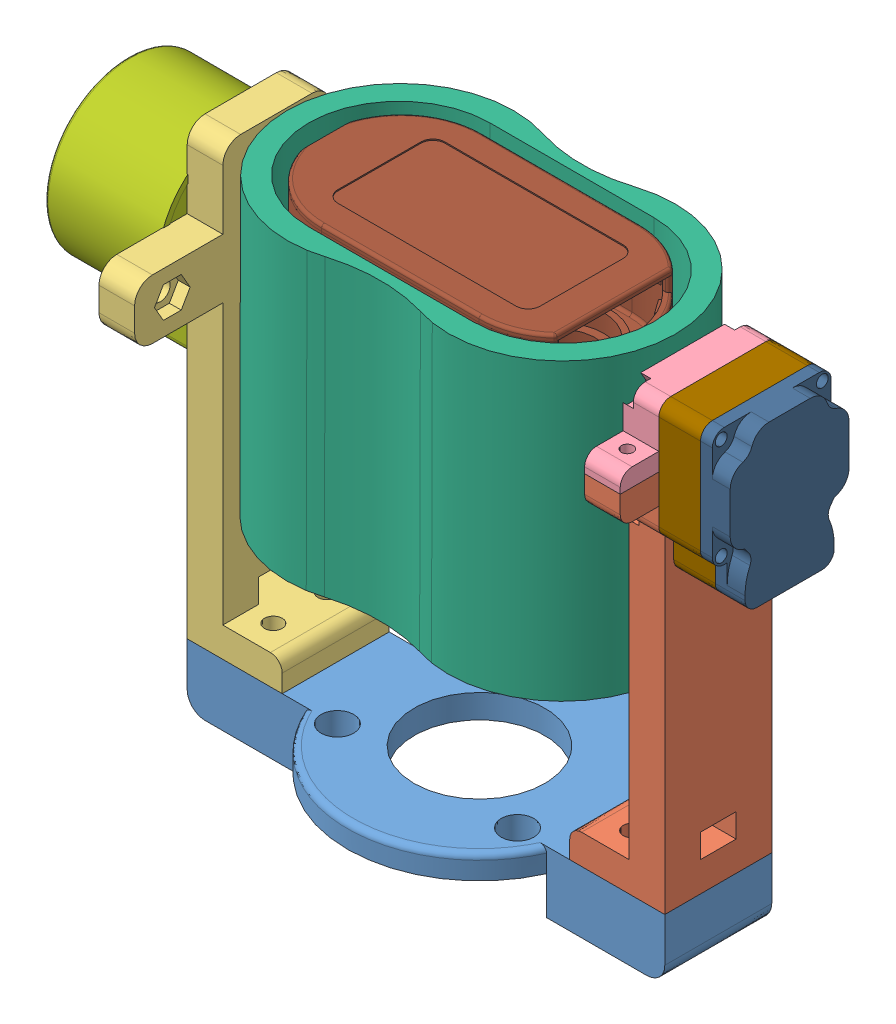
SolidWorks assembly rotating_disk, configuration Default. Lengths in mm.
Overall size (111.27 86.88 47.85).
11 component instances, 11 part files, 27 mates.
Components (placement in the parent):
- rotating_disk_base-1: rotating_disk_base [Default] at (36.4219 21.8509 71.9564) size (80.37 10.47 44.4)
- rotating_disk_encoder_arm-1: rotating_disk_encoder_arm [Default] at (36.4219 21.8509 71.9564) size (16 65 33)
- rotating_disk_stepper_arm-1: rotating_disk_stepper_arm [Default] at (36.4219 21.8509 71.9564) size (16 75 47.85)
- rotating_disk_bearing_holder-1: rotating_disk_bearing_holder [Default] at (66.6873 100.8509 78.7505) size (6 10 33)
- ball_bearing_lidar-1: ball_bearing_lidar [Default] at (74.4089 100.8509 71.9564) x (0 1 0) z (0 0 1) size (12 3.5 12)
- SF10 _attachemnt-1: SF10 _attachemnt [Default] at (36.715 71.7562 116.9127) x (-1 0 0) z (0 -0.999997 0.002567) size (83.46 38.1 49.67)
- Step - 28BYJ-48-1: Step - 28BYJ-48 [Varsayılan] at (-22.665 92.8509 71.9564) x (0 0 -1) z (0 -1 0) size (42 28.9 33.48)
- stepper_encoder-1: stepper_encoder [Default] at (79.195 100.8509 71.9564) x (0 0.002567 0.999997) z (0 -0.999997 0.002567) size (17.8 5 17.8)
- stepper_encoder_case-1: stepper_encoder_case [Default] at (76.6089 100.8509 71.9564) x (0 0 1) z (0 1 0) size (20 7 26)
- stepper_encoder_case_cap-1: stepper_encoder_case_cap [Default] at (83.6089 100.8509 71.9564) x (0 -1 0) z (0 0 1) size (26 5 20)
- sf30c-2: sf30c [Default] at (36.715 98.0933 72.1094) x (1 0 0) z (0 0.999997 -0.002567) size (57.98 31.85 50.31)
Mates (geometry in assembly coordinates):
- Concentric1: concentric aligned: cylinder of rotating_disk_base-1 through (66.6089 -64.1491 67.4564) axis (0 1 0) radius 1.5; cylinder of rotating_disk_encoder_arm-1 through (66.6089 30.8509 67.4564) axis (0 1 0) radius 1.5
- Concentric3: concentric aligned: cylinder of rotating_disk_base-1 through (66.6089 -64.1491 76.4564) axis (0 1 0) radius 1.5; cylinder of rotating_disk_encoder_arm-1 through (66.6089 30.8509 76.4564) axis (0 1 0) radius 1.5
- Coincident2: coincident anti-aligned: plane of rotating_disk_base-1 through (36.4219 35.8509 71.9564) normal (0 1 0); plane of rotating_disk_encoder_arm-1 through (97.3886 35.8509 135.9564) normal (0 -1 0)
- Concentric4: concentric aligned: cylinder of rotating_disk_base-1 through (6.235 -64.1491 76.4564) axis (0 1 0) radius 1.5; cylinder of rotating_disk_stepper_arm-1 through (6.235 -59.1491 76.4564) axis (0 1 0) radius 1.5
- Concentric5: concentric aligned: cylinder of rotating_disk_base-1 through (6.235 -64.1491 67.4564) axis (0 1 0) radius 1.5; cylinder of rotating_disk_stepper_arm-1 through (6.235 -59.1491 67.4564) axis (0 1 0) radius 1.5
- Coincident3: coincident anti-aligned: plane of rotating_disk_base-1 through (36.4219 35.8509 71.9564) normal (0 1 0); plane of rotating_disk_stepper_arm-1 through (-19.0868 35.8509 32.9564) normal (0 -1 0)
- Concentric6: concentric aligned: cylinder of rotating_disk_encoder_arm-1 through (73.6089 89.8509 84.2564) axis (0 1 0) radius 1; cylinder of rotating_disk_bearing_holder-1 through (73.6089 100.0509 84.2564) axis (0 1 0) radius 1
- Concentric7: concentric aligned: cylinder of rotating_disk_encoder_arm-1 through (73.6089 89.8509 59.6564) axis (0 1 0) radius 1; cylinder of rotating_disk_bearing_holder-1 through (73.6089 100.0509 59.6564) axis (0 1 0) radius 1
- Coincident4: coincident anti-aligned: plane of rotating_disk_encoder_arm-1 through (66.6089 100.8509 27.5829) normal (0 1 0); plane of rotating_disk_bearing_holder-1 through (66.6873 100.8509 78.7505) normal (0 -1 0)
- Coincident5: coincident anti-aligned: plane of rotating_disk_bearing_holder-1 through (74.4089 100.8509 71.9564) normal (-1 0 0); plane of ball_bearing_lidar-1 through (74.4089 100.8509 71.9564) normal (1 0 0)
- Concentric8: concentric anti-aligned: cylinder of rotating_disk_bearing_holder-1 through (113.6089 100.8509 71.9564) axis (-1 0 0) radius 5.05; cylinder of ball_bearing_lidar-1 through (70.9089 100.8509 71.9564) axis (1 0 0) radius 4
- Concentric9: concentric anti-aligned: cylinder of ball_bearing_lidar-1 through (70.9089 100.8509 71.9564) axis (1 0 0) radius 4; cylinder of SF10 _attachemnt-1 through (73.195 100.8509 71.9564) axis (-1 0 0) radius 4
- Concentric12: concentric anti-aligned: circle of rotating_disk_stepper_arm-1; cylinder of Step - 28BYJ-48-1 through (-3.765 92.8509 89.4564) axis (-1 0 0) radius 2
- Concentric13: concentric aligned: circle of rotating_disk_stepper_arm-1; circle of Step - 28BYJ-48-1
- Coincident8: coincident anti-aligned: plane of SF10 _attachemnt-1 through (6.235 100.8509 71.9564) normal (-1 0 0); plane of Step - 28BYJ-48-1 through (6.235 101.3509 71.9564) normal (1 0 0)
- Coincident9: coincident anti-aligned: plane of rotating_disk_stepper_arm-1 through (-3.765 60.4422 71.9564) normal (-1 0 0); plane of Step - 28BYJ-48-1 through (-3.765 92.8509 71.9564) normal (1 0 0)
- Coincident12: coincident anti-aligned: plane of rotating_disk_bearing_holder-1 through (76.6089 103.8509 55.4564) normal (1 0 0); plane of stepper_encoder_case-1 through (76.6089 92.8509 79.9564) normal (-1 0 0)
- Concentric26: concentric anti-aligned: cylinder of SF10 _attachemnt-1 through (80.695 102.6149 71.9518) axis (0 0.999997 -0.002567) radius 1; cylinder of stepper_encoder-1 through (80.695 115.8508 71.9179) axis (0 -0.999997 0.002567) radius 1
- Concentric27: concentric aligned: cylinder of SF10 _attachemnt-1 through (73.195 100.8509 71.9564) axis (-1 0 0) radius 4; cylinder of stepper_encoder-1 through (92.195 100.8509 71.9564) axis (-1 0 0) radius 4.075
- Coincident13: coincident anti-aligned: circle of rotating_disk_bearing_holder-1; cylinder of stepper_encoder_case-1 through (91.6089 109.3509 80.4564) axis (-1 0 0) radius 1
- Concentric28: concentric anti-aligned: cylinder of rotating_disk_bearing_holder-1 through (61.6089 109.3509 63.4564) axis (1 0 0) radius 1; cylinder of stepper_encoder_case-1 through (91.6089 109.3509 63.4564) axis (-1 0 0) radius 1
- Coincident14: coincident aligned: circle of stepper_encoder_case-1; cylinder of stepper_encoder_case_cap-1 through (98.6089 109.3509 80.4564) axis (-1 0 0) radius 1
- Coincident15: coincident aligned: cylinder of stepper_encoder_case-1 through (91.6089 109.3509 63.4564) axis (-1 0 0) radius 1; circle of stepper_encoder_case_cap-1
- Coincident16: coincident anti-aligned: plane of stepper_encoder_case-1 through (83.6089 92.3509 80.4564) normal (1 0 0); plane of stepper_encoder_case_cap-1 through (83.6089 92.8509 63.9564) normal (-1 0 0)
- Parallel4: parallel anti-aligned: plane of SF10 _attachemnt-1 through (50.4945 68.6321 87.2791) normal (0 -0.002567 -0.999997); plane of sf30c-2 through (36.715 98.1254 84.6094) normal (0 0.002567 0.999997)
- Concentric36: concentric aligned: cylinder of SF10 _attachemnt-1 through (36.715 68.6217 83.2151) axis (0 0.999997 -0.002567) radius 1.1303; cylinder of sf30c-2 through (36.715 61.6217 83.2331) axis (0 0.999997 -0.002567) radius 1.55
- Coincident18: coincident anti-aligned: plane of SF10 _attachemnt-1 through (50.4945 68.593 72.0392) normal (0 0.999997 -0.002567); plane of sf30c-2 through (49.8972 68.6344 88.1851) normal (0 -0.999997 0.002567)
